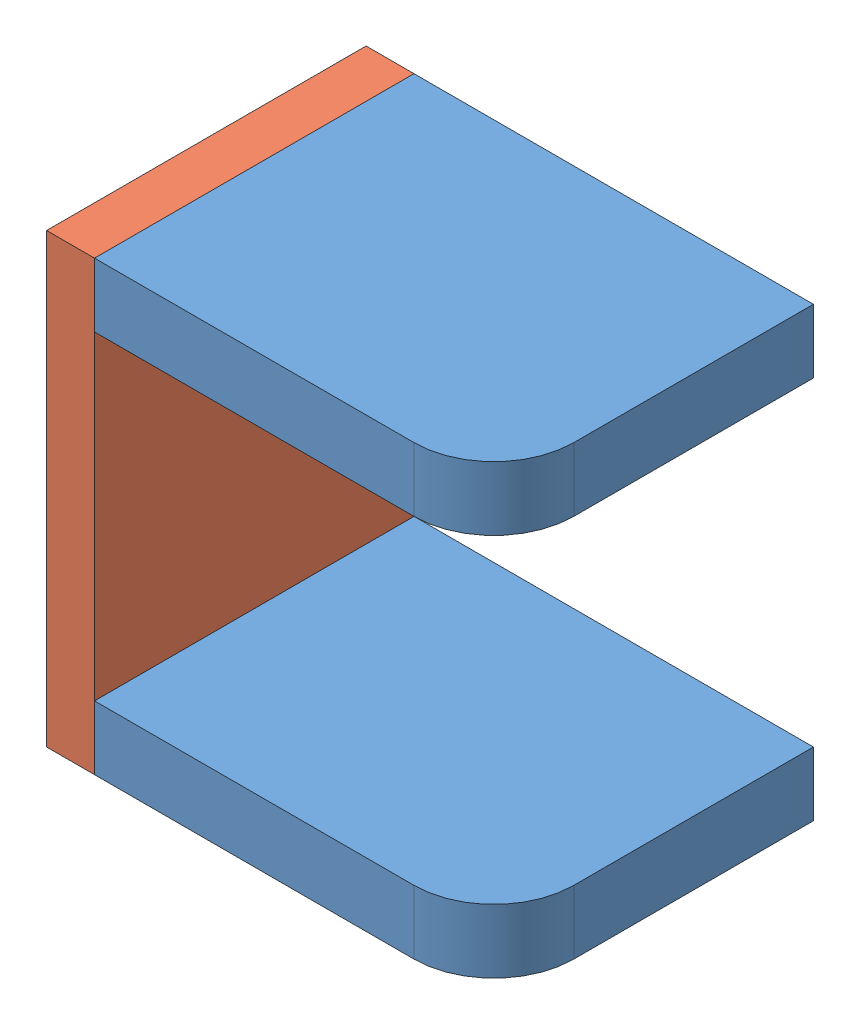
SolidWorks assembly carriage_axis_y_console, configuration По умолчанию. Lengths in mm.
Overall size (56 56 40).
3 component instances, 2 part files, 7 mates.
Components (placement in the parent):
- carriage_axis_y_console_plywood-1: carriage_axis_y_console_plywood [По умолчанию] at (25 0 0) size (50 8 40)
- carriage_axis_y_console_adge_plywood-2: carriage_axis_y_console_adge_plywood [По умолчанию] x (0 0 1) z (-1 0 0) size (40 56 6)
- carriage_axis_y_console_plywood-2: carriage_axis_y_console_plywood [По умолчанию] at (25 -48 0) size (50 8 40)
Mates (geometry in assembly coordinates):
- На месте1: in place: plane of ? through (0 28 20) normal (-1 0 0); plane of carriage_axis_y_console_adge_plywood-2 through (0 0 0) normal (-1 0 0); moOrthogonalPlaneRef_w of ? through (0 28 20) normal (-1 0 0); plane of carriage_axis_y_console_adge_plywood-2 through (0 0 0) normal (0 1 0); plane of ? through (0 28 20) normal (-1 0 0); plane of carriage_axis_y_console_adge_plywood-2 through (0 0 0) normal (0 0 1); plane of carriage_axis_y_console_plywood-1 through (0 8 20) normal (-1 0 0); unknown of carriage_axis_y_console_adge_plywood-2
- Совпадение6: coincident aligned: plane of ?; plane of ?
- Совпадение7: coincident aligned: moOrthogonalPlaneRef_w of carriage_axis_y_console_plywood-1 through (0 0 0) normal (0 1 0); plane of Деталь4^carriage_axis_y_console-1 through (0 0 0) normal (0 1 0)
- Совпадение8: coincident anti-aligned: moOrthogonalPlaneRef_w of carriage_axis_y_console_plywood-1 through (0 0 0) normal (0 0 -1); plane of Деталь4^carriage_axis_y_console-1 through (0 0 0) normal (0 0 1)
- Расстояние1: distance = 40 mm anti-aligned: plane of carriage_axis_y_console_plywood-2 through (40 -40 10) normal (0 1 0); plane of carriage_axis_y_console_plywood-1 through (40 0 10) normal (0 -1 0)
- Совпадение10: coincident aligned: plane of carriage_axis_y_console_plywood-1 through (0 8 -20) normal (0 0 -1); plane of carriage_axis_y_console_plywood-2 through (0 -40 -20) normal (0 0 -1)
- Совпадение11: coincident aligned: plane of carriage_axis_y_console_plywood-1 through (0 8 20) normal (-1 0 0); plane of carriage_axis_y_console_plywood-2 through (0 -40 20) normal (-1 0 0)
